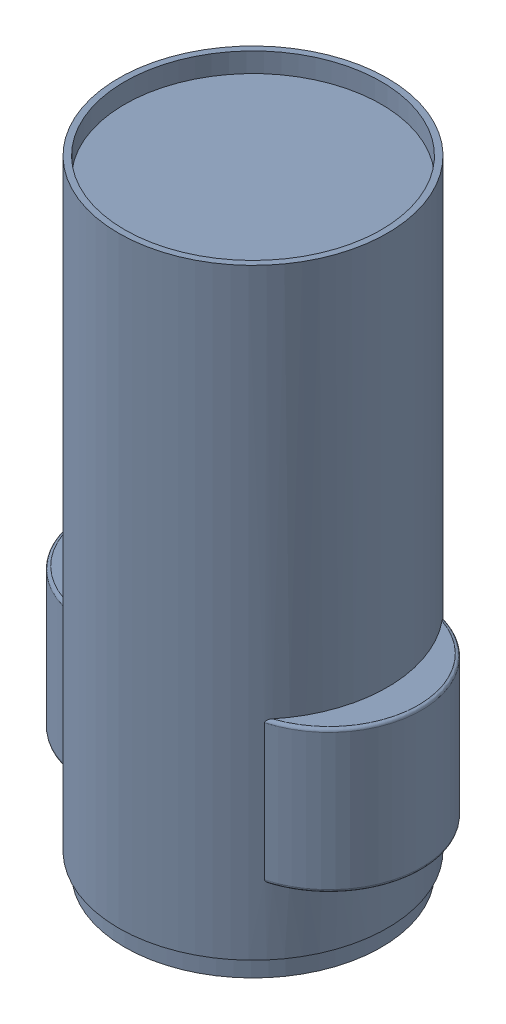
SolidWorks assembly B2714, configuration Default. Lengths in mm.
Overall size (111.5 205.8 89).
2 component instances, 1 part files, 0 mates.
Components (placement in the parent):
- B2571-1: B2571 [Default] at origin size (111.5 205.8 89)
- B1995-1: B1995 [woLabels] at (0 -73.49 0) x (0 0 1) z (0 1 0) (suppressed, hidden)
